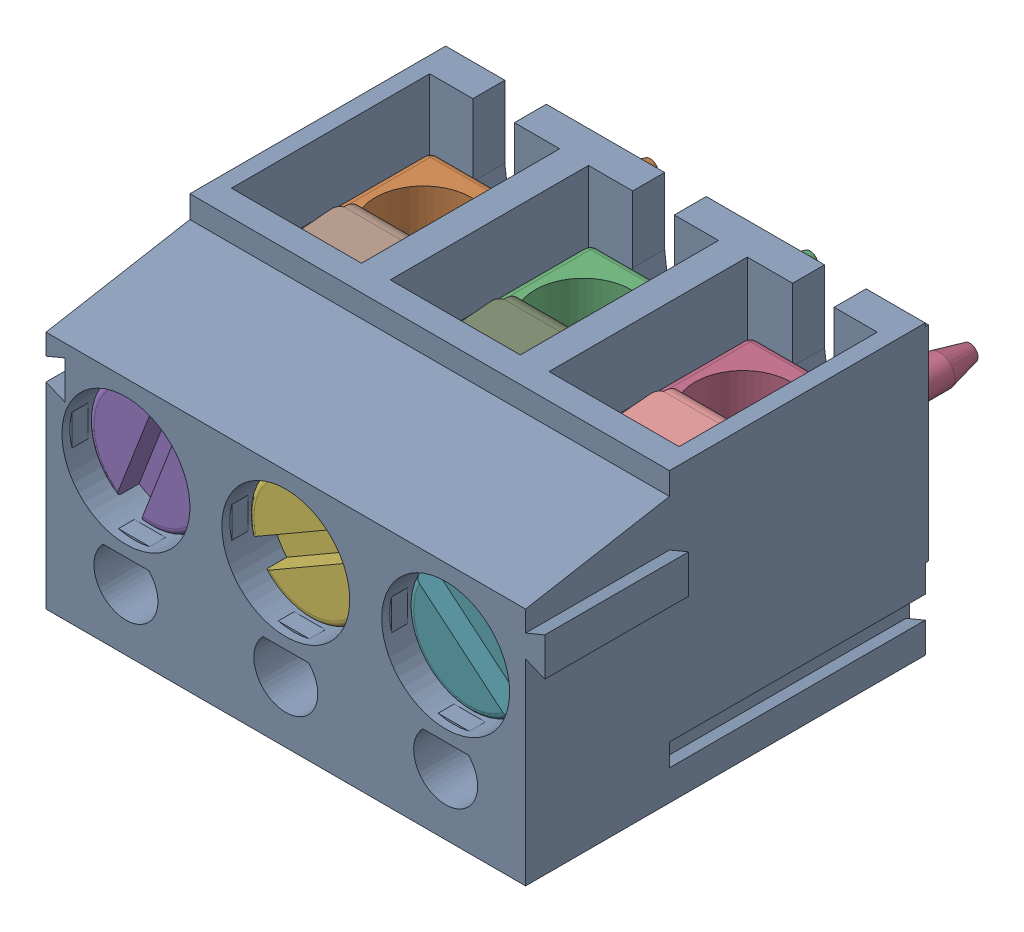
SolidWorks assembly J5, configuration Default. Lengths in mm.
Overall size (16.2 9 16.4).
11 component instances, 4 part files, 0 mates.
Components (placement in the parent):
- 691101710003-1: 691101710003 [Default] at (33.7819 56.6419 0) x (-1 0 0) z (0 0 1) size (16.2 9 16.4)
  - 6911017100xx_1-1: 6911017100xx_1 [Default] at origin size (16.2 9 12.6)
  - 6911017100xx_2-1: 6911017100xx_2 [Default] at (5 0 4) size (3.95 4 10.9)
  - 6911017100xx_2-2: 6911017100xx_2 [Default] at (0 0 4) size (3.95 4 10.9)
  - 6911017100xx_2-3: 6911017100xx_2 [Default] at (-5 0 4) size (3.95 4 10.9)
  - 6911017100xx_3-1: 6911017100xx_3 [Default] at (5 0 11.75) x (0.93283 -0.360317 0) z (0 0 1) size (3.9 3.9 7.08)
  - 6911017100xx_3-2: 6911017100xx_3 [Default] at (0 0 11.75) x (0.5 -0.866025 0) z (0 0 1) size (3.9 3.9 7.08)
  - 6911017100xx_3-3: 6911017100xx_3 [Default] at (-5 0 11.75) x (-0.642788 -0.766044 0) z (0 0 1) size (3.9 3.9 7.08)
  - 6911017100xx_4-1: 6911017100xx_4 [Default] at (5 0 7.2) size (3.95 5.03 4.22)
  - 6911017100xx_4-2: 6911017100xx_4 [Default] at (0 0 7.2) size (3.95 5.03 4.22)
  - 6911017100xx_4-3: 6911017100xx_4 [Default] at (-5 0 7.2) size (3.95 5.03 4.22)
